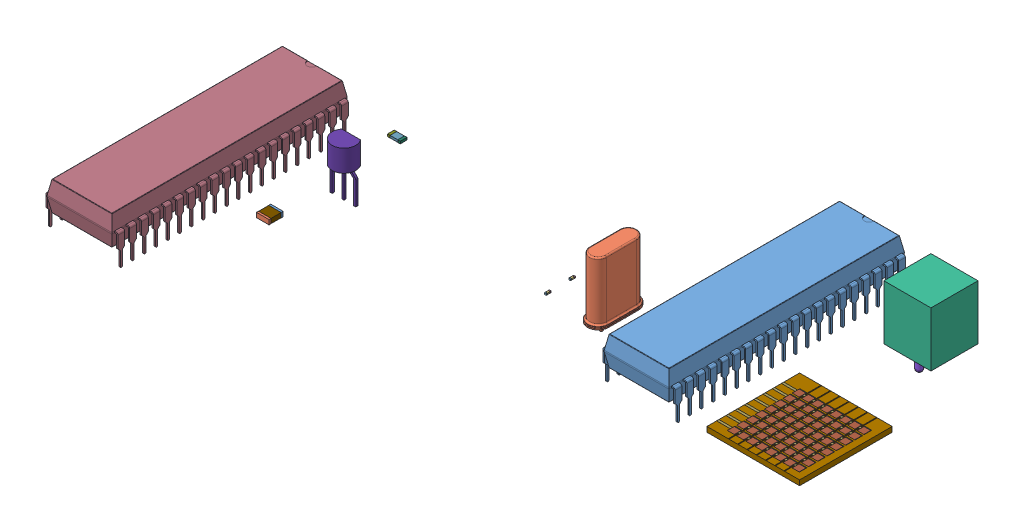
SolidWorks assembly DIGIT 5, configuration Default. Lengths in mm.
Overall size (130.6 16.91 97.86).
46 component instances, 23 part files, 0 mates.
Components (placement in the parent):
- U3-1: U3 [Default] at (-115 0.775 -55) x (0 0 1) z (0 1 0) size (50.8 15.54 9.8)
  - Open CASCADE STEP translator 6.8 1.1.1-1: Open CASCADE STEP translator 6.8 1.1.1 [Default] at origin size (50.8 15.54 9.8)
    - Body_1-1: Body_1 [Default] at (24 7.3 0) x (0 1 0) z (1 0 0) size (15.54 9.8 50.8)
- X1-1: X1 [Default] at (-124.1586 0.775 -14.4881) x (0 0 -1) z (0 1 0) size (11 4.5 15.2)
  - Open CASCADE STEP translator 6.8 1.2.1-1: Open CASCADE STEP translator 6.8 1.2.1 [Default] at origin size (11 4.5 15.2)
    - Body_1_2-1: Body_1_2 [Default] at (2.5 0 0) x (1 0 0) z (0 -1 0) size (11 15.2 4.5)
- C1-1: C1 [Default] at (-134.8402 0.775 -13.9161) x (0 0 1) z (0 1 0) size (1.04 0.4 0.33)
  - Open CASCADE STEP translator 6.8 1.3.1-1: Open CASCADE STEP translator 6.8 1.3.1 [Default] at origin size (1.04 0.4 0.33)
    - Body_1_3-1: Body_1_3 [Default] at origin size (0.73 0.38 0.31)
    - Pin_1-1: Pin_1 [Default] at origin size (0.24 0.4 0.33)
    - Pin_2-1: Pin_2 [Default] at (1.506 0 0) x (-1 0 0) z (0 0 1) size (0.24 0.4 0.33)
- C2-1: C2 [Default] at (-134.9543 0.775 -19.2815) x (0 0 1) z (0 1 0) size (1.04 0.4 0.33)
  - Open CASCADE STEP translator 6.8 1.3.1-1: Open CASCADE STEP translator 6.8 1.3.1 [Default] at origin size (1.04 0.4 0.33)
    - Body_1_3-1: Body_1_3 [Default] at origin size (0.73 0.38 0.31)
    - Pin_1-1: Pin_1 [Default] at origin size (0.24 0.4 0.33)
    - Pin_2-1: Pin_2 [Default] at (1.506 0 0) x (-1 0 0) z (0 0 1) size (0.24 0.4 0.33)
- J1-1: J1 [Default] at (-83.8696 0.775 -47.8517) x (0 0 1) z (0 1 0) size (10.16 10.16 15.71)
  - Open CASCADE STEP translator 6.8 1.5.1-1: Open CASCADE STEP translator 6.8 1.5.1 [Default] at origin size (10.16 10.16 15.71)
    - Body_1_4-1: Body_1_4 [Default] at origin size (10.16 10.16 11.8)
    - Pin_1_2-1: Pin_1_2 [Default] x (0 -1 0) z (0 0 1) size (1.42 1.42 10.52)
    - Pin_2_2-1: Pin_2_2 [Default] at (5.08 5.08 0) x (0 -1 0) z (0 0 1) size (1.42 1.42 10.52)
- Assem1-1: Assem1 [Default] at (-90.6317 -7.932 -32.3017) size (20 1.11 20)
  - glass substrate-1: glass substrate [Default] at (-2.0419 7.7484 26.5448) size (20 1.1 20)
  - pattern deposition layer(solid)-1: pattern deposition layer(solid) [Default] at (-2.0787 8.9033 26.5448) size (37.61 1.97 20.02) (hidden)
  - PDOT PSS-3: PDOT PSS [Default] at (27.0437 8.8557 10.0564) size (15.5 0 15.5)
  - Ruthenium red-1: Ruthenium red [Default] at (26.9855 8.8557 10.1147) size (15.5 0 15.5)
  - Cathode pattern deposition layer-1: Cathode pattern deposition layer [Default] at (-2.0419 8.9033 26.5448) size (37.61 1.98 20.02) (hidden)
  - Galinstan-1: Galinstan [Default] at (12.3174 8.8556 9.2101) size (18.5 0 15.5)
- wooden base-1: wooden base [Default] at (-245.402 -13.8456 66.0418) size (300 10 150) (hidden)
- atmega32-1: atmega32 [Default] at (-160.3042 1.3036 7.466) size (28.24 11.3 52.63)
  - U1-1: U1 [Default] at (-42.5 0.775 -30) x (0 0 1) z (0 1 0) size (50.8 15.54 9.8)
    - Open CASCADE STEP translator 6.8 1.1.1_1-1: Open CASCADE STEP translator 6.8 1.1.1_1 [Default] at origin size (50.8 15.54 9.8)
      - Body_1_1-1: Body_1_1 [Default] at (24 7.3 0) x (0 1 0) z (1 0 0) size (15.54 9.8 50.8)
  - R1-1: R1 [Default] at (-17.5 0.775 -32.5) x (-1 0 0) z (0 1 0) size (2.74 1.45 0.5)
    - Open CASCADE STEP translator 6.8 1.2.1_1-1: Open CASCADE STEP translator 6.8 1.2.1_1 [Default] at origin size (2.74 1.45 0.5)
      - Body_1_1_2-1: Body_1_1_2 [Default] at origin size (2.12 1.43 0.48)
      - Pin_1_1-1: Pin_1_1 [Default] at origin size (0.54 1.45 0.5)
      - Pin_2_1-1: Pin_2_1 [Default] at (4.206 0 0) x (-1 0 0) z (0 0 1) size (0.54 1.45 0.5)
  - U2-1: U2 [Default] at (-17.5 0.775 -20) x (-1 0 0) z (0 1 0) size (5.53 4.1 11.3)
    - Open CASCADE STEP translator 6.8 1.3.1-1: Open CASCADE STEP translator 6.8 1.3.1 [Default] at origin size (5.53 4.1 11.3)
      - Body_1_1_3-1: Body_1_1_3 [Default] at (0 0 2) x (-1 0 0) z (0 1 0) size (5.53 11.3 4.1)
  - C1-1: C1 [Default] at (-17.5 0.775 -5.5) x (0 0 1) z (0 1 0) size (3.07 2.7 1)
    - Open CASCADE STEP translator 6.8 1.4.1-1: Open CASCADE STEP translator 6.8 1.4.1 [Default] at origin size (3.07 2.7 1)
      - Body_1_1_4-1: Body_1_1_4 [Default] at origin size (2.71 2.68 0.98)
      - Pin_1_1_2-1: Pin_1_1_2 [Default] at (0.36 0 0) x (-1 0 0) z (0 0 1) size (0.43 2.7 1)
      - Pin_2_1_2-1: Pin_2_1_2 [Default] at origin size (0.43 2.7 1)
